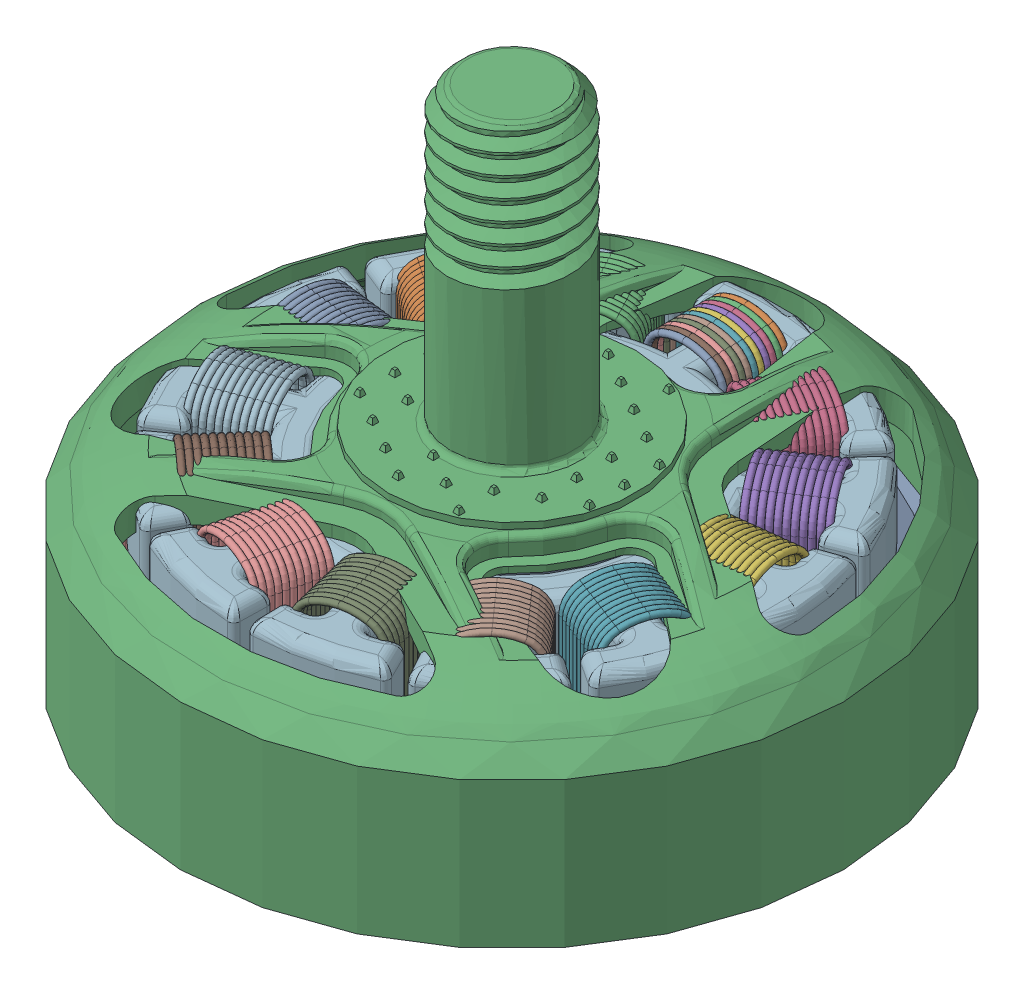
SolidWorks assembly QuadCopter Motor Assembly, configuration Default. Lengths in mm.
Overall size (26.8 23.16 26.8).
3 component instances, 3 part files, 4 mates.
Components (placement in the parent):
- QuadCopter Motor-1: QuadCopter Motor [Default] at (-11.952 -5.1403 -12.3922) size (26.8 20.89 26.8)
- QuadCopterMotor2-1: QuadCopterMotor2 [Default] at (-11.952 0.8428 -12.3922) size (22.01 4.92 22.02)
- QuadCopterMotor3-1: QuadCopterMotor3 [Default] at (-11.952 -7.4072 -12.3922) size (18 10 18)
Mates (geometry in assembly coordinates):
- Concentric3: concentric anti-aligned: circle of QuadCopter Motor-1; cylinder of QuadCopterMotor3-1 through (-11.952 2.5928 -12.3922) axis (0 1 0) radius 5.5
- Coincident7: coincident anti-aligned: plane of QuadCopter Motor-1 through (-16.9519 2.5928 -12.3922) normal (0 -1 0); plane of QuadCopterMotor3-1 through (-17.452 2.5928 -12.3922) normal (0 1 0)
- Concentric4: concentric aligned: cylinder of QuadCopter Motor-1 through (-11.952 -1.6403 -12.3922) axis (0 -1 0) radius 11.9108; cylinder of QuadCopterMotor2-1 through (-11.952 2.5928 -12.3922) axis (0 -1 0) radius 5.5
- Tangent1: tangent: plane of assembly; face of QuadCopter Motor-1; plane of QuadCopterMotor2-1 through (-11.952 2.5928 -12.3922) normal (0 1 0)
